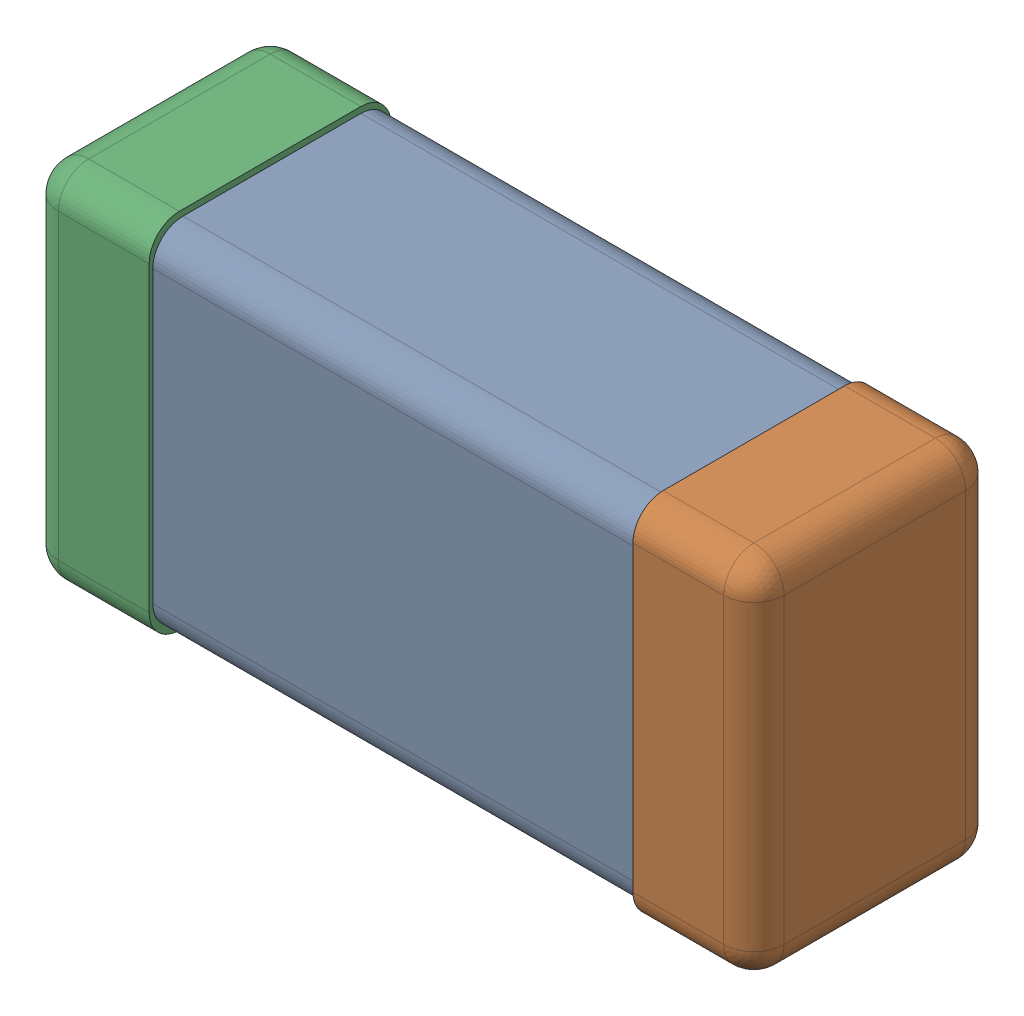
SolidWorks assembly C0201_020_28, configuration Standard. Lengths in mm.
Overall size (0.6 0.3 0.2).
4 component instances, 3 part files, 0 mates.
Components (placement in the parent):
- C0201_020_29-1: C0201_020_29 [Standard] at origin size (0.6 0.3 0.2)
  - Part 3_2-1: Part 3_2 [Standard] at (0 0 -7.3015) size (0.5 0.29 0.2)
  - Part 2_2-1: Part 2_2 [Standard] at (0 0 -7.3) size (0.1 0.3 0.2)
  - Part 1_2-1: Part 1_2 [Standard] at (0 0 -7.3) size (0.1 0.3 0.2)
